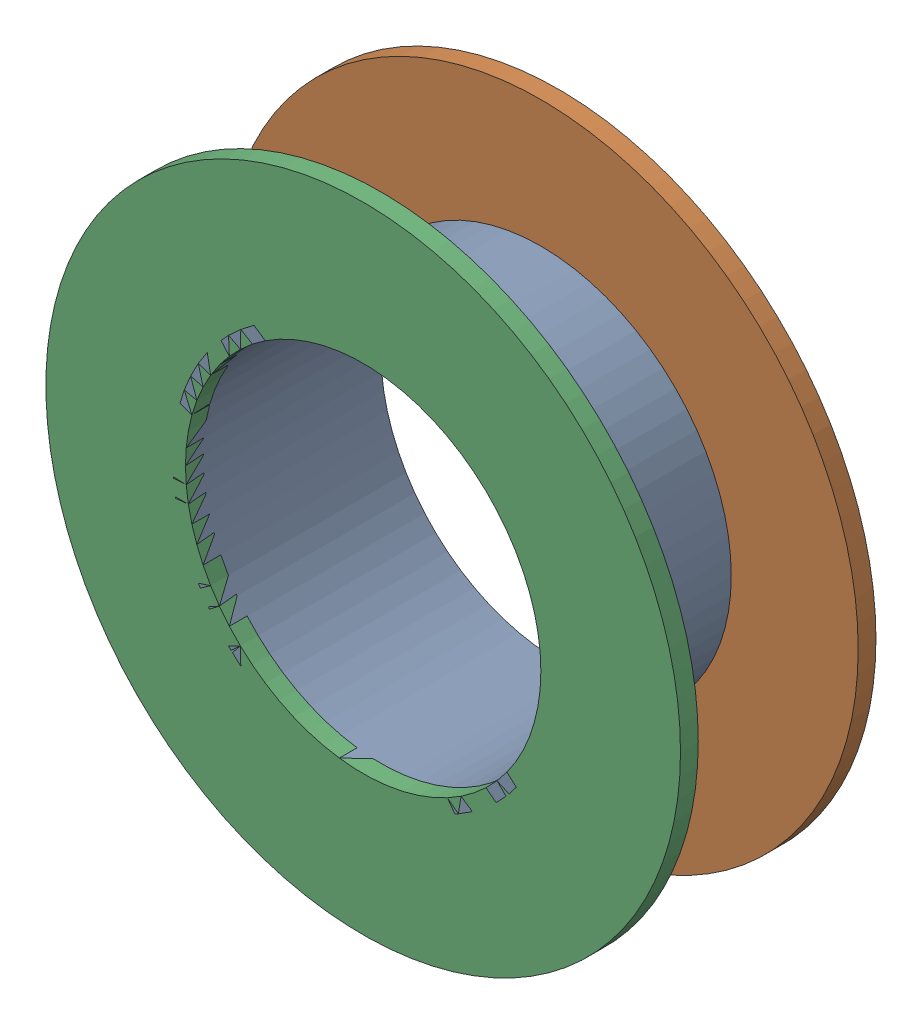
SolidWorks assembly Via (11.2mm,30.4mm) from Top Layer to Bottom Layer, configuration Predeterminado. Lengths in mm.
Overall size (1.27 1.27 0.39).
6 component instances, 2 part files, 0 mates.
Components (placement in the parent):
- Via Hole-1: Via Hole [Predeterminado] at (11.2 30.4 -0.4013) size (0.76 0.76 0.39)
  - Via Hole-Part-1-1: Via Hole-Part-1 [Predeterminado] at origin size (0.76 0.76 0.39)
- Via Top Layer-1: Via Top Layer [Predeterminado] at (11.2 30.4 -0.4013) size (1.27 1.27 0.04)
  - Via Top Layer-Part-1-1: Via Top Layer-Part-1 [Predeterminado] at origin size (1.27 1.27 0.04)
- Via Top Layer-2: Via Top Layer [Predeterminado] at (11.2 30.4 -0.0457) size (1.27 1.27 0.04)
  - Via Top Layer-Part-1-1: Via Top Layer-Part-1 [Predeterminado] at origin size (1.27 1.27 0.04)
